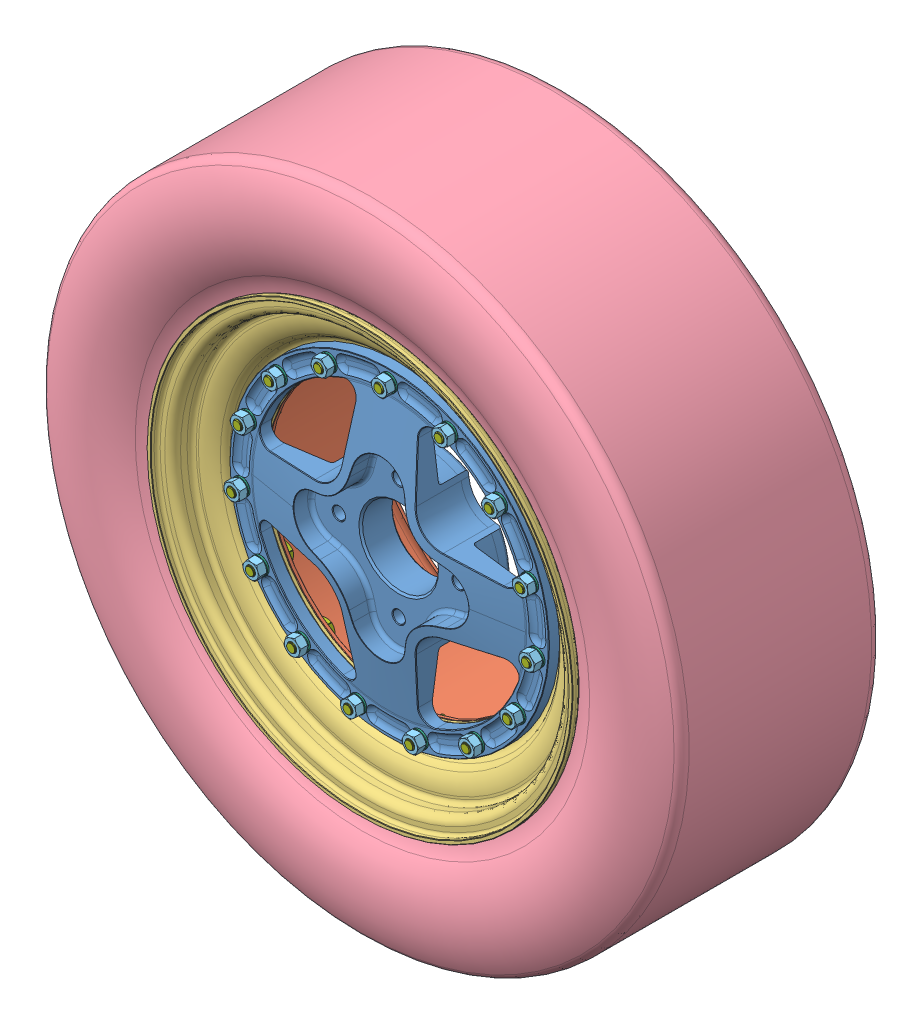
SolidWorks assembly Front Wheel, configuration Default. Lengths in mm.
Overall size (533.4 533.4 185.42).
49 component instances, 7 part files, 15 mates.
Components (placement in the parent):
- Front Center-1: Front Center [Default] at origin size (266.7 266.7 48.96)
- Front Inner Rim-1: Front Inner Rim [Default] at (0 0 -31.75) x (0 0 -1) z (1 0 0) size (134.62 355.6 355.6)
- Front Outer Rim-1: Front Outer Rim [Default] at (0 0 -31.75) size (355.6 355.6 37.46)
- Front Tire-1: Front Tire [Default] at (0 0 -78.994) x (0 0 1) z (-1 0 0) size (185.42 533.4 533.4)
- Steel Hex 5_16-18 Grade 5-1: Steel Hex 5_16-18 Grade 5 [95462A030] at (0 123.825 -13.9621) x (-0.923728 -0.383049 0) z (0 0 -1) size (12.7 14.66 8.63)
- 5_16 Small OD Washer-1: 5_16 Small OD Washer [Default] at (0 123.825 -17.3355) x (1 0 0) z (0 1 0) size (14.22 1.72 14.22)
- 5_16 Small OD Washer-17: 5_16 Small OD Washer [Default] at (50.3642 113.1198 -17.3355) x (0.913545 -0.406737 0) z (0.406737 0.913545 0) size (14.22 1.72 14.22)
- 5_16 Small OD Washer-18: 5_16 Small OD Washer [Default] at (92.0199 82.8551 -17.3355) x (0.669131 -0.743145 0) z (0.743145 0.669131 0) size (14.22 1.72 14.22)
- 5_16 Small OD Washer-19: 5_16 Small OD Washer [Default] at (117.7646 38.264 -17.3355) x (0.309017 -0.951057 0) z (0.951057 0.309017 0) size (14.22 1.72 14.22)
- 5_16 Small OD Washer-20: 5_16 Small OD Washer [Default] at (123.1467 -12.9432 -17.3355) x (-0.104528 -0.994522 0) z (0.994522 -0.104528 0) size (14.22 1.72 14.22)
- 5_16 Small OD Washer-21: 5_16 Small OD Washer [Default] at (107.2356 -61.9125 -17.3355) x (-0.5 -0.866025 0) z (0.866025 -0.5 0) size (14.22 1.72 14.22)
- 5_16 Small OD Washer-22: 5_16 Small OD Washer [Default] at (72.7825 -100.1765 -17.3355) x (-0.809017 -0.587785 0) z (0.587785 -0.809017 0) size (14.22 1.72 14.22)
- 5_16 Small OD Washer-23: 5_16 Small OD Washer [Default] at (25.7447 -121.1191 -17.3355) x (-0.978148 -0.207912 0) z (0.207912 -0.978148 0) size (14.22 1.72 14.22)
- 5_16 Small OD Washer-24: 5_16 Small OD Washer [Default] at (-25.7447 -121.1191 -17.3355) x (-0.978148 0.207912 0) z (-0.207912 -0.978148 0) size (14.22 1.72 14.22)
- 5_16 Small OD Washer-25: 5_16 Small OD Washer [Default] at (-72.7825 -100.1765 -17.3355) x (-0.809017 0.587785 0) z (-0.587785 -0.809017 0) size (14.22 1.72 14.22)
- 5_16 Small OD Washer-26: 5_16 Small OD Washer [Default] at (-107.2356 -61.9125 -17.3355) x (-0.5 0.866025 0) z (-0.866025 -0.5 0) size (14.22 1.72 14.22)
- 5_16 Small OD Washer-27: 5_16 Small OD Washer [Default] at (-123.1467 -12.9432 -17.3355) x (-0.104528 0.994522 0) z (-0.994522 -0.104528 0) size (14.22 1.72 14.22)
- 5_16 Small OD Washer-28: 5_16 Small OD Washer [Default] at (-117.7646 38.264 -17.3355) x (0.309017 0.951057 0) z (-0.951057 0.309017 0) size (14.22 1.72 14.22)
- 5_16 Small OD Washer-29: 5_16 Small OD Washer [Default] at (-92.0199 82.8551 -17.3355) x (0.669131 0.743145 0) z (-0.743145 0.669131 0) size (14.22 1.72 14.22)
- 5_16 Small OD Washer-30: 5_16 Small OD Washer [Default] at (-50.3642 113.1198 -17.3355) x (0.913545 0.406737 0) z (-0.406737 0.913545 0) size (14.22 1.72 14.22)
- Steel Hex 5_16-18 Grade 5-2: Steel Hex 5_16-18 Grade 5 [95462A030] at (50.3642 113.1198 -13.9621) x (-0.999668 0.025781 0) z (0 0 -1) size (12.7 14.66 8.63)
- Steel Hex 5_16-18 Grade 5-3: Steel Hex 5_16-18 Grade 5 [95462A030] at (92.0199 82.8551 -13.9621) x (-0.902756 0.430154 0) z (0 0 -1) size (12.7 14.66 8.63)
- Steel Hex 5_16-18 Grade 5-4: Steel Hex 5_16-18 Grade 5 [95462A030] at (117.7646 38.264 -13.9621) x (-0.649749 0.760149 0) z (0 0 -1) size (12.7 14.66 8.63)
- Steel Hex 5_16-18 Grade 5-5: Steel Hex 5_16-18 Grade 5 [95462A030] at (123.1467 -12.9432 -13.9621) x (-0.284395 0.958707 0) z (0 0 -1) size (12.7 14.66 8.63)
- Steel Hex 5_16-18 Grade 5-6: Steel Hex 5_16-18 Grade 5 [95462A030] at (107.2356 -61.9125 -13.9621) x (0.130134 0.991496 0) z (0 0 -1) size (12.7 14.66 8.63)
- Steel Hex 5_16-18 Grade 5-7: Steel Hex 5_16-18 Grade 5 [95462A030] at (72.7825 -100.1765 -13.9621) x (0.522161 0.852847 0) z (0 0 -1) size (12.7 14.66 8.63)
- Steel Hex 5_16-18 Grade 5-8: Steel Hex 5_16-18 Grade 5 [95462A030] at (25.7447 -121.1191 -13.9621) x (0.823902 0.566732 0) z (0 0 -1) size (12.7 14.66 8.63)
- Steel Hex 5_16-18 Grade 5-9: Steel Hex 5_16-18 Grade 5 [95462A030] at (-25.7447 -121.1191 -13.9621) x (0.983183 0.182625 0) z (0 0 -1) size (12.7 14.66 8.63)
- Steel Hex 5_16-18 Grade 5-10: Steel Hex 5_16-18 Grade 5 [95462A030] at (-72.7825 -100.1765 -13.9621) x (0.972462 -0.233061 0) z (0 0 -1) size (12.7 14.66 8.63)
- Steel Hex 5_16-18 Grade 5-11: Steel Hex 5_16-18 Grade 5 [95462A030] at (-107.2356 -61.9125 -13.9621) x (0.793594 -0.608447 0) z (0 0 -1) size (12.7 14.66 8.63)
- Steel Hex 5_16-18 Grade 5-12: Steel Hex 5_16-18 Grade 5 [95462A030] at (-123.1467 -12.9432 -13.9621) x (0.477506 -0.878628 0) z (0 0 -1) size (12.7 14.66 8.63)
- Steel Hex 5_16-18 Grade 5-13: Steel Hex 5_16-18 Grade 5 [95462A030] at (-117.7646 38.264 -13.9621) x (0.078854 -0.996886 0) z (0 0 -1) size (12.7 14.66 8.63)
- Steel Hex 5_16-18 Grade 5-14: Steel Hex 5_16-18 Grade 5 [95462A030] at (-92.0199 82.8551 -13.9621) x (-0.333434 -0.942774 0) z (0 0 -1) size (12.7 14.66 8.63)
- Steel Hex 5_16-18 Grade 5-15: Steel Hex 5_16-18 Grade 5 [95462A030] at (-50.3642 113.1198 -13.9621) x (-0.688067 -0.725647 0) z (0 0 -1) size (12.7 14.66 8.63)
- Steel 5_16in-18 1in Wheel-1: Steel 5_16in-18 1in Wheel [Default] at (0 123.825 -31.75) x (-1 0 0) z (0 0 -1) size (12.7 14.41 30.67)
- Steel 5_16in-18 1in Wheel-2: Steel 5_16in-18 1in Wheel [Default] at (50.3642 113.1198 -31.75) x (-0.913545 0.406737 0) z (0 0 -1) size (12.7 14.41 30.67)
- Steel 5_16in-18 1in Wheel-3: Steel 5_16in-18 1in Wheel [Default] at (92.0199 82.8551 -31.75) x (-0.669131 0.743145 0) z (0 0 -1) size (12.7 14.41 30.67)
- Steel 5_16in-18 1in Wheel-4: Steel 5_16in-18 1in Wheel [Default] at (117.7646 38.264 -31.75) x (-0.309017 0.951057 0) z (0 0 -1) size (12.7 14.41 30.67)
- Steel 5_16in-18 1in Wheel-5: Steel 5_16in-18 1in Wheel [Default] at (123.1467 -12.9432 -31.75) x (0.104528 0.994522 0) z (0 0 -1) size (12.7 14.41 30.67)
- Steel 5_16in-18 1in Wheel-6: Steel 5_16in-18 1in Wheel [Default] at (107.2356 -61.9125 -31.75) x (0.5 0.866025 0) z (0 0 -1) size (12.7 14.41 30.67)
- Steel 5_16in-18 1in Wheel-7: Steel 5_16in-18 1in Wheel [Default] at (72.7825 -100.1765 -31.75) x (0.809017 0.587785 0) z (0 0 -1) size (12.7 14.41 30.67)
- Steel 5_16in-18 1in Wheel-8: Steel 5_16in-18 1in Wheel [Default] at (25.7447 -121.1191 -31.75) x (0.978148 0.207912 0) z (0 0 -1) size (12.7 14.41 30.67)
- Steel 5_16in-18 1in Wheel-9: Steel 5_16in-18 1in Wheel [Default] at (-25.7447 -121.1191 -31.75) x (0.978148 -0.207912 0) z (0 0 -1) size (12.7 14.41 30.67)
- Steel 5_16in-18 1in Wheel-10: Steel 5_16in-18 1in Wheel [Default] at (-72.7825 -100.1765 -31.75) x (0.809017 -0.587785 0) z (0 0 -1) size (12.7 14.41 30.67)
- Steel 5_16in-18 1in Wheel-11: Steel 5_16in-18 1in Wheel [Default] at (-107.2356 -61.9125 -31.75) x (0.5 -0.866025 0) z (0 0 -1) size (12.7 14.41 30.67)
- Steel 5_16in-18 1in Wheel-12: Steel 5_16in-18 1in Wheel [Default] at (-123.1467 -12.9432 -31.75) x (0.104528 -0.994522 0) z (0 0 -1) size (12.7 14.41 30.67)
- Steel 5_16in-18 1in Wheel-13: Steel 5_16in-18 1in Wheel [Default] at (-117.7646 38.264 -31.75) x (-0.309017 -0.951057 0) z (0 0 -1) size (12.7 14.41 30.67)
- Steel 5_16in-18 1in Wheel-14: Steel 5_16in-18 1in Wheel [Default] at (-92.0199 82.8551 -31.75) x (-0.669131 -0.743145 0) z (0 0 -1) size (12.7 14.41 30.67)
- Steel 5_16in-18 1in Wheel-15: Steel 5_16in-18 1in Wheel [Default] at (-50.3642 113.1198 -31.75) x (-0.913545 -0.406737 0) z (0 0 -1) size (12.7 14.41 30.67)
Mates (geometry in assembly coordinates):
- Coincident1: coordinate: point of Front Center-1; point of assembly
- Coincident3: coincident anti-aligned: plane of Front Inner Rim-1 through (0 114.3 -31.75) normal (0 0 1); plane of Front Outer Rim-1 through (0 114.3 -31.75) normal (0 0 -1)
- Concentric3: concentric anti-aligned: cylinder of Front Inner Rim-1 through (0 0 -25.019) axis (0 0 1) radius 159.4739; cylinder of Front Outer Rim-1 through (0 0 -33.6231) axis (0 0 -1) radius 164.8473
- Concentric4: concentric aligned: cylinder of Front Inner Rim-1 through (0 123.825 -166.3706) axis (0 0 1) radius 4.4983; cylinder of Front Outer Rim-1 through (0 123.825 -31.75) axis (0 0 1) radius 4.4983
- Coincident4: coincident anti-aligned: plane of Front Center-1 through (134.5492 -134.5492 -28.575) normal (0 0 -1); plane of Front Outer Rim-1 through (0 114.3 -28.575) normal (0 0 1)
- Concentric5: concentric anti-aligned: cylinder of Front Center-1 through (0 0 -18.573) axis (0 0 -1) radius 133.35; cylinder of Front Inner Rim-1 through (0 0 -25.019) axis (0 0 1) radius 162.6489
- Concentric7: concentric aligned: cylinder of Front Center-1 through (0 123.825 -29.052) axis (0 0 1) radius 4.1021; cylinder of Front Inner Rim-1 through (0 123.825 -166.3706) axis (0 0 1) radius 4.4983
- Concentric8: concentric anti-aligned: cylinder of Front Inner Rim-1 through (0 0 -25.019) axis (0 0 1) radius 162.6489; cylinder of Front Tire-1 through (0 0 -102.1727) axis (0 0 -1) radius 261.62
- Distance1: distance = 24.384 mm anti-aligned: plane of Front Tire-1 through (0 0 -78.994) normal (0 0 1); plane of Front Center-1 through (0 0 -54.61) normal (0 0 -1)
- Coincident10: coincident anti-aligned: plane of Front Center-1 through (-134.5492 -134.5492 -19.05) normal (0 0 1); plane of 5_16 Small OD Washer-1 through (-6.9403 116.8847 -19.05) normal (0 0 -1)
- Concentric15: concentric aligned: cylinder of Front Center-1 through (0 123.825 -29.052) axis (0 0 1) radius 4.1021; cylinder of 5_16 Small OD Washer-1 through (0 123.825 -18.9167) axis (0 0 1) radius 4.064
- Coincident13: coincident anti-aligned: plane of Steel Hex 5_16-18 Grade 5-1 through (4.4613 129.6439 -17.3355) normal (0 0 -1); plane of 5_16 Small OD Washer-1 through (-6.9403 116.8847 -17.3355) normal (0 0 1)
- Concentric16: concentric aligned: cylinder of Front Center-1 through (0 123.825 -29.052) axis (0 0 1) radius 4.1021; circle of Steel Hex 5_16-18 Grade 5-1
- Concentric17: concentric anti-aligned: cylinder of Front Center-1 through (0 123.825 -29.052) axis (0 0 1) radius 4.1021; circle of Steel 5_16in-18 1in Wheel-1
- Coincident14: coincident anti-aligned: plane of Front Inner Rim-1 through (0 114.3 -34.925) normal (0 0 -1); plane of Steel 5_16in-18 1in Wheel-1 through (6.35 116.5332 -34.925) normal (0 0 1)
